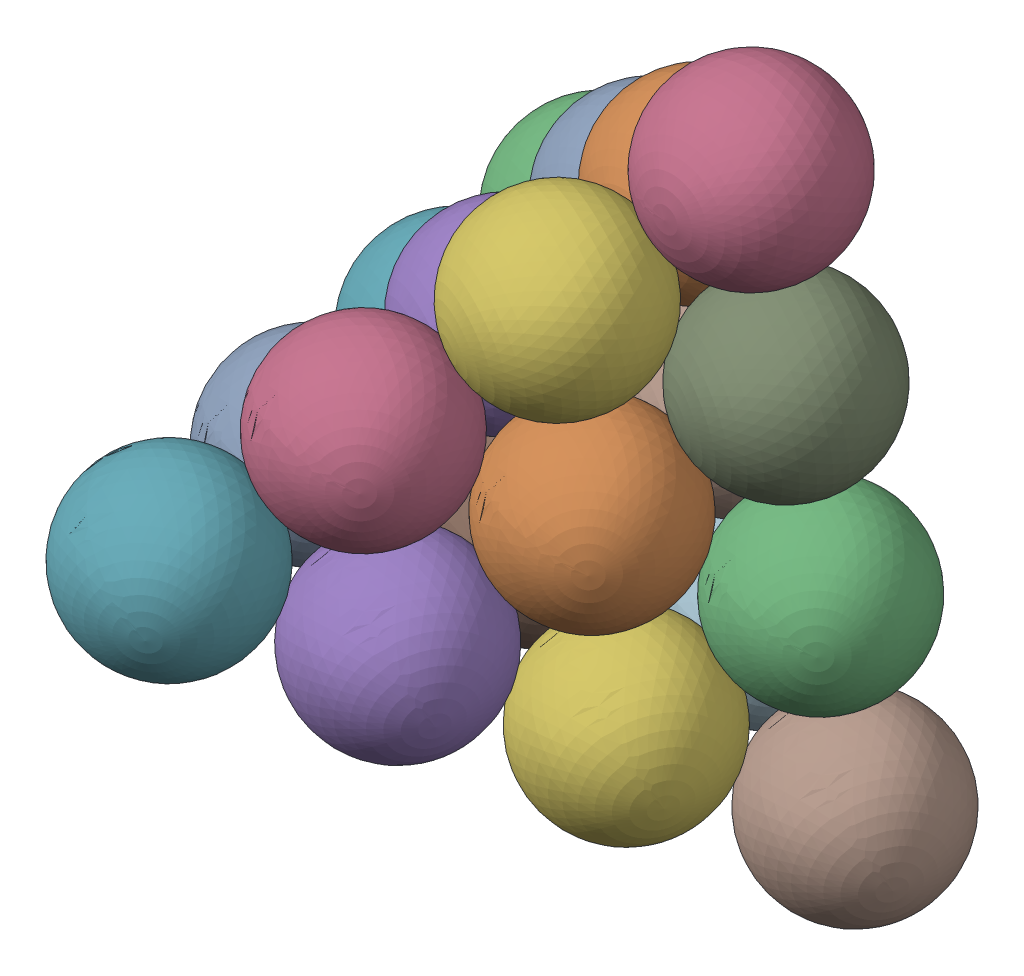
SolidWorks assembly Assem1, configuration Default. Lengths in mm.
Overall size (240.94 311.81 310.75).
26 component instances, 1 part files, 26 mates.
Components (placement in the parent):
- Assem7-1: Assem7 [Default] at (68.3107 70.0751 105.4186) size (197.77 184.43 148.49)
  - secondhalfpart1-5: secondhalfpart1 [Default] at (-48.0249 6.0494 60) size (60 60 60)
  - secondhalfpart1-6: secondhalfpart1 [Default] at (-7.0114 42.7606 83.8784) size (60 60 60)
  - secondhalfpart1-7: secondhalfpart1 [Default] at (-97.3425 -42.7188 32.3069) x (0.912105 0.17596 0.370275) z (-0.276803 -0.4019 0.872844) size (60 60 60)
  - secondhalfpart1-8: secondhalfpart1 [Default] at (33.9889 79.4689 107.7839) size (60 60 60)
- Assem6-1: Assem6 [Default] at (63.6872 91.0129 178.2337) x (0.718115 0.565447 0.405685) z (-0.350249 -0.210078 0.912794) size (179.8 66.94 60.57)
  - secondhalfpart1-13: secondhalfpart1 [Default] at (-26.1588 7.5409 60) size (60 60 60)
  - secondhalfpart1-14: secondhalfpart1 [Default] at (33.74 11.0133 59.7154) size (60 60 60)
  - secondhalfpart1-15: secondhalfpart1 [Default] at (-86.0575 4.0685 60.2846) size (60 60 60)
- Assem6-3: Assem6 [Default] at (106.4224 66.8617 141.9517) x (0.71612 0.565172 0.409576) z (-0.399523 -0.14925 0.904492) size (179.8 66.94 60.57)
  - secondhalfpart1-13: secondhalfpart1 [Default] at (-26.1588 7.5409 60) size (60 60 60)
  - secondhalfpart1-14: secondhalfpart1 [Default] at (33.74 11.0133 59.7154) size (60 60 60)
  - secondhalfpart1-15: secondhalfpart1 [Default] at (-86.0575 4.0685 60.2846) size (60 60 60)
- Assem6-4: Assem6 [Default] at (35.2809 -4.5066 158.722) x (0.683256 -0.422666 -0.595411) z (0.692529 0.116648 0.711897) size (179.8 66.94 60.57)
  - secondhalfpart1-13: secondhalfpart1 [Default] at (-26.1588 7.5409 60) size (60 60 60)
  - secondhalfpart1-14: secondhalfpart1 [Default] at (33.74 11.0133 59.7154) size (60 60 60)
  - secondhalfpart1-15: secondhalfpart1 [Default] at (-86.0575 4.0685 60.2846) size (60 60 60)
- Assem6-5: Assem6 [Default] at (76.3228 33.4393 181.8127) x (0.681223 -0.422661 -0.59774) z (0.683183 0.073645 0.726524) size (179.8 66.94 60.57)
  - secondhalfpart1-13: secondhalfpart1 [Default] at (-26.1588 7.5409 60) size (60 60 60)
  - secondhalfpart1-14: secondhalfpart1 [Default] at (33.74 11.0133 59.7154) size (60 60 60)
  - secondhalfpart1-15: secondhalfpart1 [Default] at (-86.0575 4.0685 60.2846) size (60 60 60)
- Assem7-3: Assem7 [Default] at (24.0557 -22.1428 219.1022) x (0.078058 -0.861459 -0.501792) z (0.877005 -0.180022 0.445482) size (197.77 184.43 148.49)
  - secondhalfpart1-5: secondhalfpart1 [Default] at (-48.0249 6.0494 60) size (60 60 60)
  - secondhalfpart1-6: secondhalfpart1 [Default] at (-7.0114 42.7606 83.8784) size (60 60 60)
  - secondhalfpart1-7: secondhalfpart1 [Default] at (-97.3425 -42.7188 32.3069) x (0.912105 0.17596 0.370275) z (-0.276803 -0.4019 0.872844) size (60 60 60)
  - secondhalfpart1-8: secondhalfpart1 [Default] at (33.9889 79.4689 107.7839) size (60 60 60)
Mates (geometry in assembly coordinates):
- Tangent14: tangent anti-aligned: sphere of Assem7-1/secondhalfpart1-5; sphere of Assem6-1/secondhalfpart1-13
- Tangent15: tangent anti-aligned: sphere of Assem7-1/secondhalfpart1-6; sphere of Assem6-1/secondhalfpart1-13
- Tangent16: tangent anti-aligned: sphere of Assem7-1/secondhalfpart1-6; sphere of Assem6-1/secondhalfpart1-14
- Tangent17: tangent anti-aligned: sphere of Assem7-1/secondhalfpart1-5; sphere of Assem6-1/secondhalfpart1-15
- Tangent24: tangent anti-aligned: sphere of Assem6-1/secondhalfpart1-15; sphere of Assem6-4/secondhalfpart1-15
- Tangent25: tangent anti-aligned: sphere of Assem6-1/secondhalfpart1-15; sphere of Assem6-4/secondhalfpart1-13
- Tangent26: tangent anti-aligned: sphere of Assem6-1/secondhalfpart1-15; sphere of Assem6-3/secondhalfpart1-15
- Tangent30: tangent anti-aligned: sphere of Assem7-1/secondhalfpart1-6; sphere of Assem6-3/secondhalfpart1-14
- Tangent31: tangent anti-aligned: sphere of Assem7-1/secondhalfpart1-8; sphere of Assem6-3/secondhalfpart1-14
- Tangent33: tangent anti-aligned: sphere of Assem6-1/secondhalfpart1-14; sphere of Assem6-5/secondhalfpart1-15
- Tangent36: tangent anti-aligned: sphere of Assem6-4/secondhalfpart1-15; sphere of Assem6-5/secondhalfpart1-15
- Tangent39: tangent anti-aligned: sphere of Assem6-3/secondhalfpart1-14; sphere of Assem6-5/secondhalfpart1-14
- Tangent40: tangent anti-aligned: sphere of Assem6-4/secondhalfpart1-13; sphere of Assem6-5/secondhalfpart1-13
- Tangent42: tangent anti-aligned: sphere of Assem6-3/secondhalfpart1-15; sphere of Assem6-4/secondhalfpart1-14
- Tangent43: tangent anti-aligned: sphere of Assem7-1/secondhalfpart1-7; sphere of Assem6-3/secondhalfpart1-15
- Tangent50: tangent anti-aligned: sphere of Assem6-3/secondhalfpart1-14; sphere of Assem6-5/secondhalfpart1-14
- Tangent51: tangent anti-aligned: sphere of Assem7-1/secondhalfpart1-8; sphere of Assem6-3/secondhalfpart1-14
- Tangent56: tangent anti-aligned: sphere of Assem6-1/secondhalfpart1-14; sphere of Assem6-3/secondhalfpart1-14
- Tangent57: tangent anti-aligned: sphere of Assem6-1/secondhalfpart1-13; sphere of Assem6-5/secondhalfpart1-15
- Tangent59: tangent anti-aligned: sphere of Assem6-3/secondhalfpart1-13; sphere of Assem6-4/secondhalfpart1-14
- Tangent64: tangent anti-aligned: sphere of Assem6-3/secondhalfpart1-14; sphere of Assem6-5/secondhalfpart1-13
- Tangent69: tangent anti-aligned: sphere of Assem6-5/secondhalfpart1-15; sphere of Assem7-3/secondhalfpart1-7
- Tangent70: tangent anti-aligned: sphere of Assem6-4/secondhalfpart1-13; sphere of Assem7-3/secondhalfpart1-5
- Tangent71: tangent anti-aligned: sphere of Assem6-4/secondhalfpart1-14; sphere of Assem7-3/secondhalfpart1-8
- Tangent73: tangent anti-aligned: sphere of Assem6-4/secondhalfpart1-15; sphere of Assem7-3/secondhalfpart1-7
- Tangent75: tangent anti-aligned: sphere of Assem6-5/secondhalfpart1-14; sphere of Assem7-3/secondhalfpart1-6
